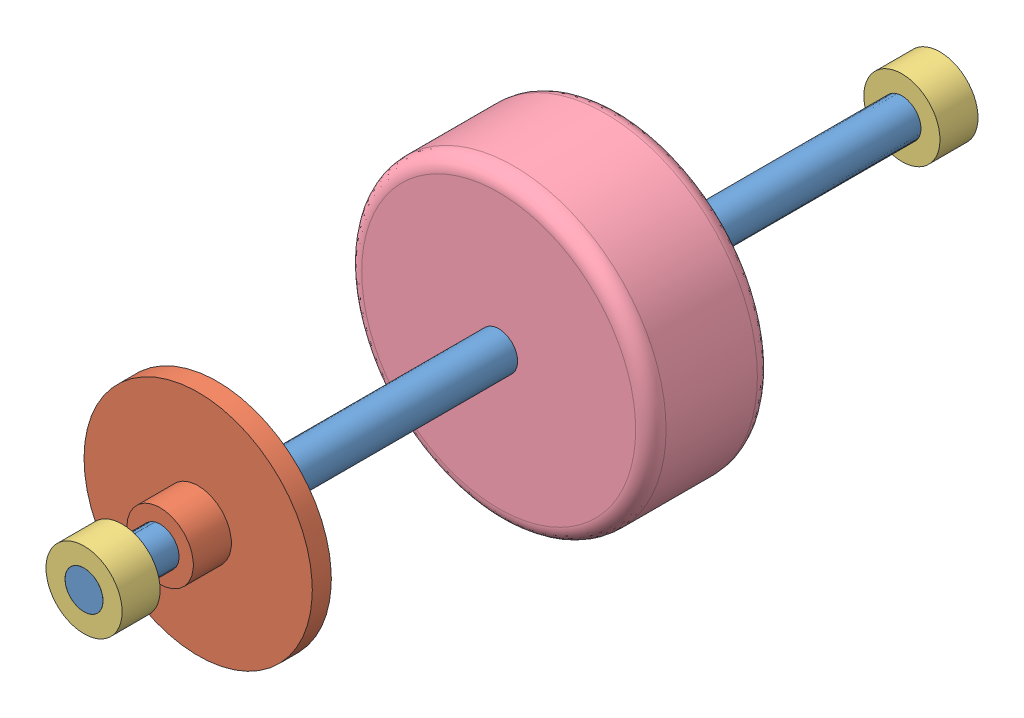
SolidWorks assembly Back Wheel Assembly, configuration Default. Lengths in mm.
Overall size (50.8 50.8 142.88).
5 component instances, 4 part files, 8 mates.
Components (placement in the parent):
- Back Axel-1: Back Axel [Default] at (52.9609 75.4335 37.8334) size (6.35 6.35 142.88)
- 72-Gear-1: 72-Gear [Default] at (52.9609 75.4335 158.4834) size (38.1 38.1 9.53)
- Axel Washer-1: Axel Washer [Default] at (52.9609 75.4335 174.3584) size (12.7 12.7 6.35)
- Axel Washer-2: Axel Washer [Default] at (52.9609 75.4335 37.8334) size (12.7 12.7 6.35)
- Wheel-1: Wheel [Default] at (52.9609 75.4335 91.1734) size (50.8 50.8 20.32)
Mates (geometry in assembly coordinates):
- Coincident1: coincident aligned: plane of Back Axel-1 through (52.9609 75.4335 180.7084) normal (0 0 1); plane of Axel Washer-1 through (52.9609 75.4335 180.7084) normal (0 0 1)
- Concentric1: concentric aligned: cylinder of Back Axel-1 through (52.9609 75.4335 180.7084) axis (0 0 -1) radius 3.175; cylinder of Axel Washer-1 through (52.9609 75.4335 180.7084) axis (0 0 -1) radius 3.175
- Coincident2: coincident aligned: plane of Back Axel-1 through (52.9609 75.4335 37.8334) normal (0 0 -1); plane of Axel Washer-2 through (52.9609 75.4335 37.8334) normal (0 0 -1)
- Concentric2: concentric aligned: cylinder of Back Axel-1 through (52.9609 75.4335 180.7084) axis (0 0 -1) radius 3.175; cylinder of Axel Washer-2 through (52.9609 75.4335 44.1834) axis (0 0 -1) radius 3.175
- Distance1: distance = 6.35 mm anti-aligned: plane of 72-Gear-1 through (52.9609 75.4335 168.0084) normal (0 0 1); plane of Axel Washer-1 through (52.9609 75.4335 174.3584) normal (0 0 -1)
- Concentric3: concentric aligned: cylinder of Back Axel-1 through (52.9609 75.4335 180.7084) axis (0 0 -1) radius 3.175; cylinder of 72-Gear-1 through (52.9609 75.4335 168.0084) axis (0 0 -1) radius 3.175
- Distance2: distance = 53.34 mm aligned: plane of Back Axel-1 through (52.9609 75.4335 37.8334) normal (0 0 -1); plane of Wheel-1 through (52.9609 75.4335 91.1734) normal (0 0 -1)
- Concentric4: concentric aligned: cylinder of Back Axel-1 through (52.9609 75.4335 180.7084) axis (0 0 -1) radius 3.175; cylinder of Wheel-1 through (52.9609 75.4335 111.4934) axis (0 0 -1) radius 3.175
